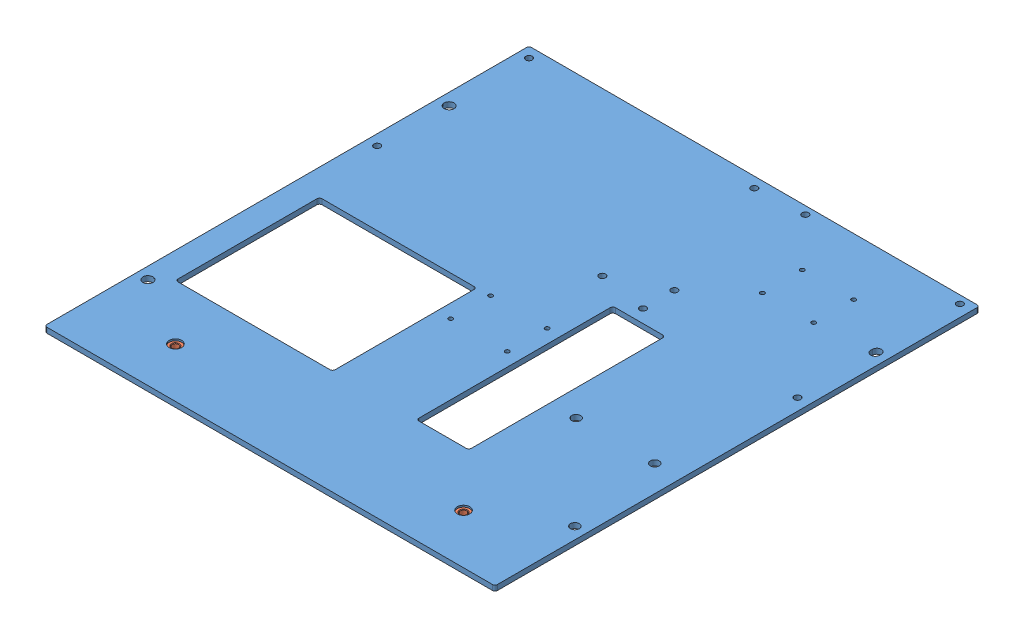
SolidWorks assembly HEL-03-01010-00, configuration Standard. Lengths in mm.
Overall size (172 4 185).
3 component instances, 2 part files, 4 mates.
Components (placement in the parent):
- HEL-04-01010-01-1: HEL-04-01010-01 [Standard] at origin size (172 2 185)
- aluminum nut_pmm-1: aluminum nut_pmm [PEM CLA-M3-2 ---N] at (55 0 73.5) x (0.837169 0 0.546944) z (0.546944 0 -0.837169) size (6.3 3.37 6.3)
- aluminum nut_pmm-2: aluminum nut_pmm [PEM CLA-M3-2 ---N] at (-55 0 73.5) x (0.837169 0 0.546944) z (0.546944 0 -0.837169) size (6.3 3.37 6.3)
Mates (geometry in assembly coordinates):
- Konzentrisch1: concentric aligned: cylinder of HEL-04-01010-01-1 through (55 2 73.5) axis (0 1 0) radius 2.395; cylinder of aluminum nut_pmm-1 through (55 0 73.5) axis (0 1 0) radius 3.15
- Deckungsgleich1: coincident anti-aligned: plane of HEL-04-01010-01-1 through (0 0 0) normal (0 -1 0); plane of aluminum nut_pmm-1 through (56.715 0 74.6205) normal (0 1 0)
- Konzentrisch2: concentric aligned: cylinder of HEL-04-01010-01-1 through (-55 2 73.5) axis (0 1 0) radius 2.395; cylinder of aluminum nut_pmm-2 through (-55 0 73.5) axis (0 1 0) radius 3.15
- Deckungsgleich2: coincident anti-aligned: plane of HEL-04-01010-01-1 through (0 0 0) normal (0 -1 0); plane of aluminum nut_pmm-2 through (-53.285 0 74.6205) normal (0 1 0)
